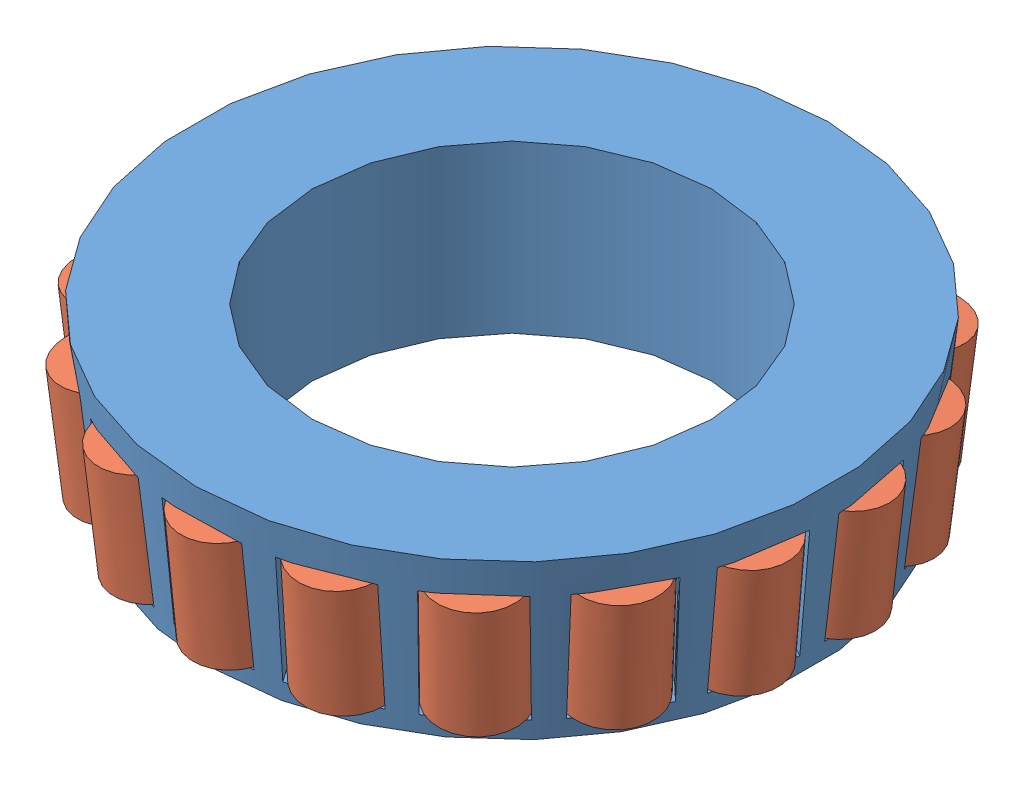
SolidWorks assembly Idler Wheel Bearing Assembly, configuration Default. Lengths in mm.
Overall size (5.14 1.27 5.06).
19 component instances, 2 part files, 36 mates.
Components (placement in the parent):
- idler Wheel Bearing-1: idler Wheel Bearing [Default] at (-0.759 1.0051 -0.2823) size (4.83 1.27 4.83)
- Idler Wheel Bearing Roller-1: Idler Wheel Bearing Roller [Default] at (-0.759 -0.1093 1.8348) x (-0.999426 -0.00354 0.033681) z (0 0.994522 0.104528) size (0.64 0.64 0.89)
- Idler Wheel Bearing Roller-2: Idler Wheel Bearing Roller [Default] at (-2.6729 0.7749 -1.3873) x (0.789274 0.103648 0.60523) z (0.090524 -0.994522 0.052264) size (0.64 0.64 0.89)
- Idler Wheel Bearing Roller-3: Idler Wheel Bearing Roller [Default] at (-0.759 0.7749 -2.4923) x (1 0 0) z (0 -0.994522 0.104528) size (0.64 0.64 0.89)
- Idler Wheel Bearing Roller-4: Idler Wheel Bearing Roller [Default] at (-0.0031 0.7749 -2.3591) x (0.927484 0.003582 0.373846) z (-0.035751 -0.994522 0.098225) size (0.64 0.64 0.89)
- Idler Wheel Bearing Roller-5: Idler Wheel Bearing Roller [Default] at (-2.1199 -0.1093 1.3395) x (0.99582 0.061868 0.06719) z (-0.06719 0.994522 0.080073) size (0.64 0.64 0.89)
- Idler Wheel Bearing Roller-6: Idler Wheel Bearing Roller [Default] at (-2.8439 -0.1093 0.0853) x (0.979533 0.098182 0.175711) z (-0.10294 0.994522 0.018151) size (0.64 0.64 0.89)
- Idler Wheel Bearing Roller-7: Idler Wheel Bearing Roller [Default] at (-2.1796 0.7749 -1.9753) x (0.99582 0.061868 -0.06719) z (0.06719 -0.994522 0.080073) size (0.64 0.64 0.89)
- Idler Wheel Bearing Roller-8: Idler Wheel Bearing Roller [Default] at (-2.5925 -0.1093 0.7762) x (0.992212 0.085557 0.090524) z (-0.090524 0.994522 0.052264) size (0.64 0.64 0.89)
- Idler Wheel Bearing Roller-9: Idler Wheel Bearing Roller [Default] at (-1.4831 -0.1093 1.7071) x (0.998836 0.032375 0.035751) z (-0.035751 0.994522 0.098225) size (0.64 0.64 0.89)
- Idler Wheel Bearing Roller-10: Idler Wheel Bearing Roller [Default] at (-1.5149 0.7749 -2.3591) x (0.998836 0.032375 -0.035751) z (0.035751 -0.994522 0.098225) size (0.64 0.64 0.89)
- Idler Wheel Bearing Roller-11: Idler Wheel Bearing Roller [Default] at (-2.9355 0.7749 -0.6661) x (0.986505 0.104412 0.126122) z (0.10294 -0.994522 0.018151) size (0.64 0.64 0.89)
- Idler Wheel Bearing Roller-12: Idler Wheel Bearing Roller [Default] at (1.4174 0.7749 -0.6661) x (0.885883 -0.083366 0.456356) z (-0.10294 -0.994522 0.018151) size (0.64 0.64 0.89)
- Idler Wheel Bearing Roller-13: Idler Wheel Bearing Roller [Default] at (1.0745 -0.1093 0.7762) x (0.992212 -0.085557 -0.090524) z (0.090524 0.994522 0.052264) size (0.64 0.64 0.89)
- Idler Wheel Bearing Roller-14: Idler Wheel Bearing Roller [Default] at (0.6018 -0.1093 1.3395) x (0.874291 -0.097355 0.47554) z (0.06719 0.994522 0.080073) size (0.64 0.64 0.89)
- Idler Wheel Bearing Roller-15: Idler Wheel Bearing Roller [Default] at (0.6616 0.7749 -1.9753) x (0.913673 -0.093574 -0.395532) z (-0.06719 -0.994522 0.080073) size (0.64 0.64 0.89)
- Idler Wheel Bearing Roller-16: Idler Wheel Bearing Roller [Default] at (1.1549 0.7749 -1.3873) x (0.899555 -0.059136 0.432785) z (-0.090524 -0.994522 0.052264) size (0.64 0.64 0.89)
- Idler Wheel Bearing Roller-17: Idler Wheel Bearing Roller [Default] at (1.3259 -0.1093 0.0853) x (0.989592 -0.100551 -0.10294) z (0.10294 0.994522 0.018151) size (0.64 0.64 0.89)
- Idler Wheel Bearing Roller-18: Idler Wheel Bearing Roller [Default] at (-0.0349 -0.1093 1.7071) x (0.70634 -0.094677 0.701512) z (0.035751 0.994522 0.098225) size (0.64 0.64 0.89)
Mates (geometry in assembly coordinates):
- Concentric1: concentric anti-aligned: cylinder of idler Wheel Bearing-1 through (-0.759 -0.1093 1.8348) axis (0 0.994522 0.104528) radius 0.3429; cylinder of Idler Wheel Bearing Roller-1 through (-0.759 0.7749 1.9277) axis (0 -0.994522 -0.104528) radius 0.3175
- Coincident1: coincident anti-aligned: plane of idler Wheel Bearing-1 through (-0.759 -0.1093 1.8348) normal (0 0.994522 0.104528); plane of Idler Wheel Bearing Roller-1 through (-0.759 -0.1093 1.8348) normal (0 -0.994522 -0.104528)
- Concentric2: concentric anti-aligned: cylinder of idler Wheel Bearing-1 through (-1.4831 -0.1093 1.7071) axis (-0.035751 0.994522 0.098225) radius 0.3429; cylinder of Idler Wheel Bearing Roller-9 through (-1.5149 0.7749 1.7944) axis (0.035751 -0.994522 -0.098225) radius 0.3175
- Concentric3: concentric anti-aligned: cylinder of idler Wheel Bearing-1 through (-2.1199 -0.1093 1.3395) axis (-0.06719 0.994522 0.080073) radius 0.3429; cylinder of Idler Wheel Bearing Roller-5 through (-2.1796 0.7749 1.4107) axis (0.06719 -0.994522 -0.080073) radius 0.3175
- Concentric4: concentric anti-aligned: cylinder of idler Wheel Bearing-1 through (-2.5925 -0.1093 0.7762) axis (-0.090524 0.994522 0.052264) radius 0.3429; cylinder of Idler Wheel Bearing Roller-8 through (-2.6729 0.7749 0.8227) axis (0.090524 -0.994522 -0.052264) radius 0.3175
- Concentric5: concentric anti-aligned: cylinder of idler Wheel Bearing-1 through (-2.8439 -0.1093 0.0853) axis (-0.10294 0.994522 0.018151) radius 0.3429; cylinder of Idler Wheel Bearing Roller-6 through (-2.9355 0.7749 0.1015) axis (0.10294 -0.994522 -0.018151) radius 0.3175
- Concentric6: concentric aligned: cylinder of idler Wheel Bearing-1 through (-2.8439 -0.1093 -0.6499) axis (-0.10294 0.994522 -0.018151) radius 0.3429; cylinder of Idler Wheel Bearing Roller-11 through (-2.8439 -0.1093 -0.6499) axis (-0.10294 0.994522 -0.018151) radius 0.3175
- Concentric7: concentric aligned: cylinder of idler Wheel Bearing-1 through (-2.5925 -0.1093 -1.3409) axis (-0.090524 0.994522 -0.052264) radius 0.3429; cylinder of Idler Wheel Bearing Roller-2 through (-2.5925 -0.1093 -1.3409) axis (-0.090524 0.994522 -0.052264) radius 0.3175
- Concentric8: concentric aligned: cylinder of idler Wheel Bearing-1 through (-2.1199 -0.1093 -1.9041) axis (-0.06719 0.994522 -0.080073) radius 0.3429; cylinder of Idler Wheel Bearing Roller-7 through (-2.1199 -0.1093 -1.9041) axis (-0.06719 0.994522 -0.080073) radius 0.3175
- Concentric9: concentric aligned: cylinder of idler Wheel Bearing-1 through (-1.4831 -0.1093 -2.2717) axis (-0.035751 0.994522 -0.098225) radius 0.3429; cylinder of Idler Wheel Bearing Roller-10 through (-1.4831 -0.1093 -2.2717) axis (-0.035751 0.994522 -0.098225) radius 0.3175
- Concentric10: concentric aligned: cylinder of idler Wheel Bearing-1 through (-0.759 -0.1093 -2.3994) axis (0 0.994522 -0.104528) radius 0.3429; cylinder of Idler Wheel Bearing Roller-3 through (-0.759 -0.1093 -2.3994) axis (0 0.994522 -0.104528) radius 0.3175
- Concentric11: concentric aligned: cylinder of idler Wheel Bearing-1 through (-0.0349 -0.1093 -2.2717) axis (0.035751 0.994522 -0.098225) radius 0.3429; cylinder of Idler Wheel Bearing Roller-4 through (-0.0349 -0.1093 -2.2717) axis (0.035751 0.994522 -0.098225) radius 0.3175
- Concentric12: concentric aligned: cylinder of idler Wheel Bearing-1 through (0.6018 -0.1093 -1.9041) axis (0.06719 0.994522 -0.080073) radius 0.3429; cylinder of Idler Wheel Bearing Roller-15 through (0.6018 -0.1093 -1.9041) axis (0.06719 0.994522 -0.080073) radius 0.3175
- Concentric13: concentric aligned: cylinder of idler Wheel Bearing-1 through (1.0745 -0.1093 -1.3409) axis (0.090524 0.994522 -0.052264) radius 0.3429; cylinder of Idler Wheel Bearing Roller-16 through (1.0745 -0.1093 -1.3409) axis (0.090524 0.994522 -0.052264) radius 0.3175
- Concentric14: concentric aligned: cylinder of idler Wheel Bearing-1 through (1.3259 -0.1093 -0.6499) axis (0.10294 0.994522 -0.018151) radius 0.3429; cylinder of Idler Wheel Bearing Roller-12 through (1.3259 -0.1093 -0.6499) axis (0.10294 0.994522 -0.018151) radius 0.3175
- Concentric15: concentric anti-aligned: cylinder of idler Wheel Bearing-1 through (1.3259 -0.1093 0.0853) axis (0.10294 0.994522 0.018151) radius 0.3429; cylinder of Idler Wheel Bearing Roller-17 through (1.4174 0.7749 0.1015) axis (-0.10294 -0.994522 -0.018151) radius 0.3175
- Concentric16: concentric anti-aligned: cylinder of idler Wheel Bearing-1 through (1.0745 -0.1093 0.7762) axis (0.090524 0.994522 0.052264) radius 0.3429; cylinder of Idler Wheel Bearing Roller-13 through (1.1549 0.7749 0.8227) axis (-0.090524 -0.994522 -0.052264) radius 0.3175
- Concentric17: concentric anti-aligned: cylinder of idler Wheel Bearing-1 through (0.6018 -0.1093 1.3395) axis (0.06719 0.994522 0.080073) radius 0.3429; cylinder of Idler Wheel Bearing Roller-14 through (0.6616 0.7749 1.4107) axis (-0.06719 -0.994522 -0.080073) radius 0.3175
- Concentric18: concentric anti-aligned: cylinder of idler Wheel Bearing-1 through (-0.0349 -0.1093 1.7071) axis (0.035751 0.994522 0.098225) radius 0.3429; cylinder of Idler Wheel Bearing Roller-18 through (-0.0031 0.7749 1.7944) axis (-0.035751 -0.994522 -0.098225) radius 0.3175
- Coincident2: coincident anti-aligned: plane of idler Wheel Bearing-1 through (-1.5149 0.7749 1.7944) normal (0.035751 -0.994522 -0.098225); plane of Idler Wheel Bearing Roller-9 through (-1.5149 0.7749 1.7944) normal (-0.035751 0.994522 0.098225)
- Coincident3: coincident anti-aligned: plane of idler Wheel Bearing-1 through (-2.1796 0.7749 1.4107) normal (0.06719 -0.994522 -0.080073); plane of Idler Wheel Bearing Roller-5 through (-2.1796 0.7749 1.4107) normal (-0.06719 0.994522 0.080073)
- Coincident4: coincident anti-aligned: plane of idler Wheel Bearing-1 through (-2.6729 0.7749 0.8227) normal (0.090524 -0.994522 -0.052264); plane of Idler Wheel Bearing Roller-8 through (-2.6729 0.7749 0.8227) normal (-0.090524 0.994522 0.052264)
- Coincident5: coincident anti-aligned: plane of idler Wheel Bearing-1 through (-2.9355 0.7749 0.1015) normal (0.10294 -0.994522 -0.018151); plane of Idler Wheel Bearing Roller-6 through (-2.9355 0.7749 0.1015) normal (-0.10294 0.994522 0.018151)
- Coincident6: coincident anti-aligned: plane of idler Wheel Bearing-1 through (-2.9355 0.7749 -0.6661) normal (0.10294 -0.994522 0.018151); plane of Idler Wheel Bearing Roller-11 through (-2.9355 0.7749 -0.6661) normal (-0.10294 0.994522 -0.018151)
- Coincident7: coincident anti-aligned: plane of idler Wheel Bearing-1 through (-2.6729 0.7749 -1.3873) normal (0.090524 -0.994522 0.052264); plane of Idler Wheel Bearing Roller-2 through (-2.6729 0.7749 -1.3873) normal (-0.090524 0.994522 -0.052264)
- Coincident8: coincident anti-aligned: plane of idler Wheel Bearing-1 through (-2.1796 0.7749 -1.9753) normal (0.06719 -0.994522 0.080073); plane of Idler Wheel Bearing Roller-7 through (-2.1796 0.7749 -1.9753) normal (-0.06719 0.994522 -0.080073)
- Coincident9: coincident anti-aligned: plane of idler Wheel Bearing-1 through (-1.5149 0.7749 -2.3591) normal (0.035751 -0.994522 0.098225); plane of Idler Wheel Bearing Roller-10 through (-1.5149 0.7749 -2.3591) normal (-0.035751 0.994522 -0.098225)
- Coincident10: coincident anti-aligned: plane of idler Wheel Bearing-1 through (-0.759 0.7749 -2.4923) normal (0 -0.994522 0.104528); plane of Idler Wheel Bearing Roller-3 through (-0.759 0.7749 -2.4923) normal (0 0.994522 -0.104528)
- Coincident11: coincident anti-aligned: plane of idler Wheel Bearing-1 through (-0.0031 0.7749 -2.3591) normal (-0.035751 -0.994522 0.098225); plane of Idler Wheel Bearing Roller-4 through (-0.0031 0.7749 -2.3591) normal (0.035751 0.994522 -0.098225)
- Coincident12: coincident anti-aligned: plane of idler Wheel Bearing-1 through (0.6616 0.7749 -1.9753) normal (-0.06719 -0.994522 0.080073); plane of Idler Wheel Bearing Roller-15 through (0.6616 0.7749 -1.9753) normal (0.06719 0.994522 -0.080073)
- Coincident13: coincident anti-aligned: plane of idler Wheel Bearing-1 through (1.1549 0.7749 -1.3873) normal (-0.090524 -0.994522 0.052264); plane of Idler Wheel Bearing Roller-16 through (1.1549 0.7749 -1.3873) normal (0.090524 0.994522 -0.052264)
- Coincident14: coincident anti-aligned: plane of idler Wheel Bearing-1 through (1.4174 0.7749 -0.6661) normal (-0.10294 -0.994522 0.018151); plane of Idler Wheel Bearing Roller-12 through (1.4174 0.7749 -0.6661) normal (0.10294 0.994522 -0.018151)
- Coincident15: coincident anti-aligned: plane of idler Wheel Bearing-1 through (1.4174 0.7749 0.1015) normal (-0.10294 -0.994522 -0.018151); plane of Idler Wheel Bearing Roller-17 through (1.4174 0.7749 0.1015) normal (0.10294 0.994522 0.018151)
- Coincident16: coincident anti-aligned: plane of idler Wheel Bearing-1 through (1.1549 0.7749 0.8227) normal (-0.090524 -0.994522 -0.052264); plane of Idler Wheel Bearing Roller-13 through (1.1549 0.7749 0.8227) normal (0.090524 0.994522 0.052264)
- Coincident17: coincident anti-aligned: plane of idler Wheel Bearing-1 through (0.6616 0.7749 1.4107) normal (-0.06719 -0.994522 -0.080073); plane of Idler Wheel Bearing Roller-14 through (0.6616 0.7749 1.4107) normal (0.06719 0.994522 0.080073)
- Coincident18: coincident anti-aligned: plane of idler Wheel Bearing-1 through (-0.0031 0.7749 1.7944) normal (-0.035751 -0.994522 -0.098225); plane of Idler Wheel Bearing Roller-18 through (-0.0031 0.7749 1.7944) normal (0.035751 0.994522 0.098225)
